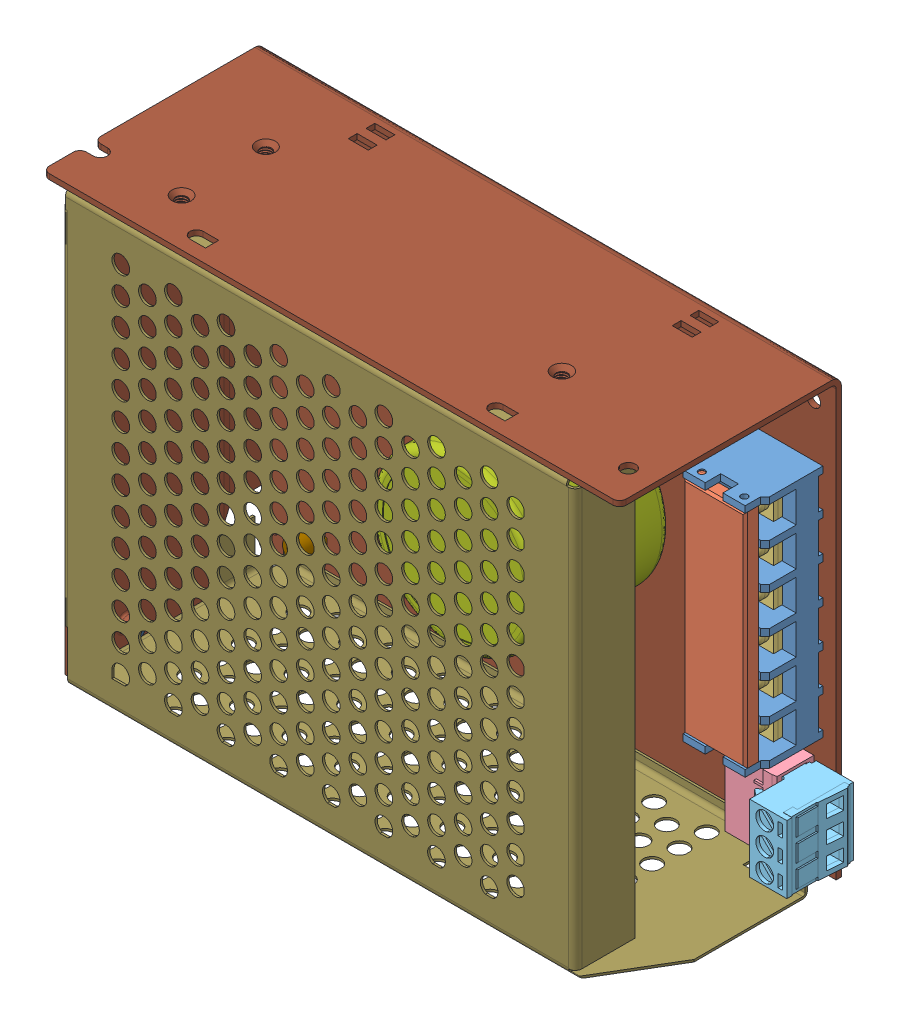
SolidWorks assembly Spindle Power supply, configuration Default. Lengths in mm.
Overall size (140.88 98 50.05).
20 component instances, 13 part files, 0 mates.
Components (placement in the parent):
- Spindle Power supply.step-1: Spindle Power supply.step [Default] at origin size (140.88 98 50.05)
  - Terminal block v1.step-1: Terminal block v1.step [Default] at (133.5 32.7893 7.7) x (0 1 0) z (0 0 1) size (53 15 16.5)
    - Component11.step-1: Component11.step [Default] at origin size (53 15 16.5)
    - Component12.step-1: Component12.step [Default] at origin size (53 14 3)
    - Terminal point.step-1: Terminal point.step [Default] at origin size (6.8 6.8 7.5)
    - Terminal point.step-2: Terminal point.step [Default] at (8.6 0 0) size (6.8 6.8 7.5)
    - Terminal point.step-3: Terminal point.step [Default] at (17.2 0 0) size (6.8 6.8 7.5)
    - Terminal point.step-4: Terminal point.step [Default] at (25.8 0 0) size (6.8 6.8 7.5)
    - Terminal point.step-5: Terminal point.step [Default] at (34.4 0 0) size (6.8 6.8 7.5)
    - Terminal point.step-6: Terminal point.step [Default] at (43 0 0) size (6.8 6.8 7.5)
  - 3P Plugin male v1.step-1: 3P Plugin male v1.step [Default] at (131.5 -18.18 7.7) x (0 1 0) z (0 0 1) size (16.84 12 12.5)
  - 3P Plugin female v1.step-1: 3P Plugin female v1.step [Default] at (132 -18.18 7.7) x (0 1 0) z (0 0 1) size (15.24 18.03 15)
  - Standoff.step-1: Standoff.step [Default] at origin size (6.93 6 5.79)
  - Capacitor.step-1: Capacitor.step [Default] at origin size (38 38 30)
  - Screw.step-1: Screw.step [Default] at origin size (7 7 7.06)
  - PCB.step-1: PCB.step [Default] at origin (suppressed, hidden)
  - Standoff (1).step-1: Standoff (1).step [Default] at origin size (6 6.93 5.8)
  - Screw (1).step-1: Screw (1).step [Default] at origin size (7.05 7 7)
  - Aluminum case.step-1: Aluminum case.step [Default] at origin size (130 98 50)
  - Cover.step-1: Cover.step [Default] at origin size (126 96.8 48.8)
